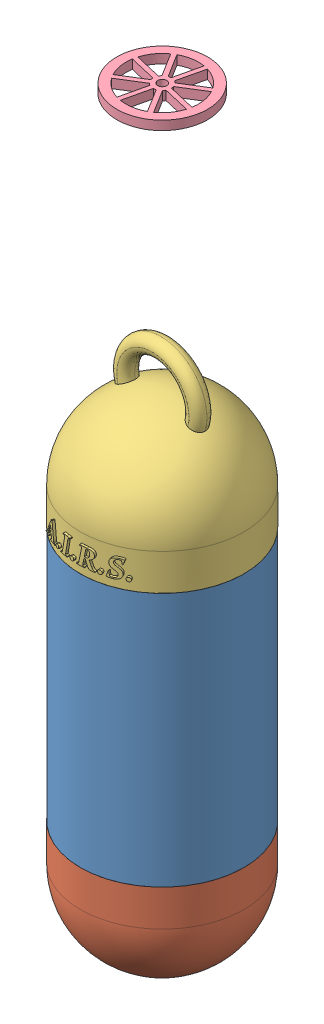
SolidWorks assembly Prototype Assembly, configuration Default. Lengths in mm.
Overall size (158.2 528.9 158.2).
4 component instances, 4 part files, 4 mates.
Components (placement in the parent):
- PVC Body-1: PVC Body [Default] at (-13.146 18.4266 168.5563) size (114.3 177.8 114.3)
- PVC Cap-1: PVC Cap [Default] at (-13.146 43.8266 168.5563) x (-0.837169 0 -0.546944) z (-0.546944 0 0.837169) size (114.3 107.95 114.3)
- PVC Opening-1: PVC Opening [Default] at (-13.146 170.8766 168.5563) x (0.999627 0 0.027292) z (-0.027292 0 0.999627) size (114.3 140.05 115.9)
- Parachute Stabilizer-1: Parachute Stabilizer [Default] at (-13.146 458.4303 168.5563) x (0.849329 0 -0.527864) z (0.527864 0 0.849329) size (63.5 6.35 63.5)
Mates (geometry in assembly coordinates):
- Concentric2: concentric anti-aligned: cylinder of PVC Body-1 through (-13.146 196.2266 168.5563) axis (0 -1 0) radius 57.15; cylinder of PVC Opening-1 through (-13.146 278.8266 168.5563) axis (0 1 0) radius 51.5938
- Coincident1: coincident anti-aligned: plane of PVC Body-1 through (-13.146 18.4266 168.5563) normal (0 -1 0); plane of PVC Cap-1 through (-57.0032 18.4266 139.9033) normal (0 1 0)
- Concentric3: concentric aligned: cylinder of PVC Body-1 through (-13.146 196.2266 168.5563) axis (0 -1 0) radius 57.15; cylinder of PVC Cap-1 through (-13.146 -64.1234 168.5563) axis (0 -1 0) radius 57.15
- Concentric4: concentric aligned: circle of PVC Opening-1; circle of Parachute Stabilizer-1
